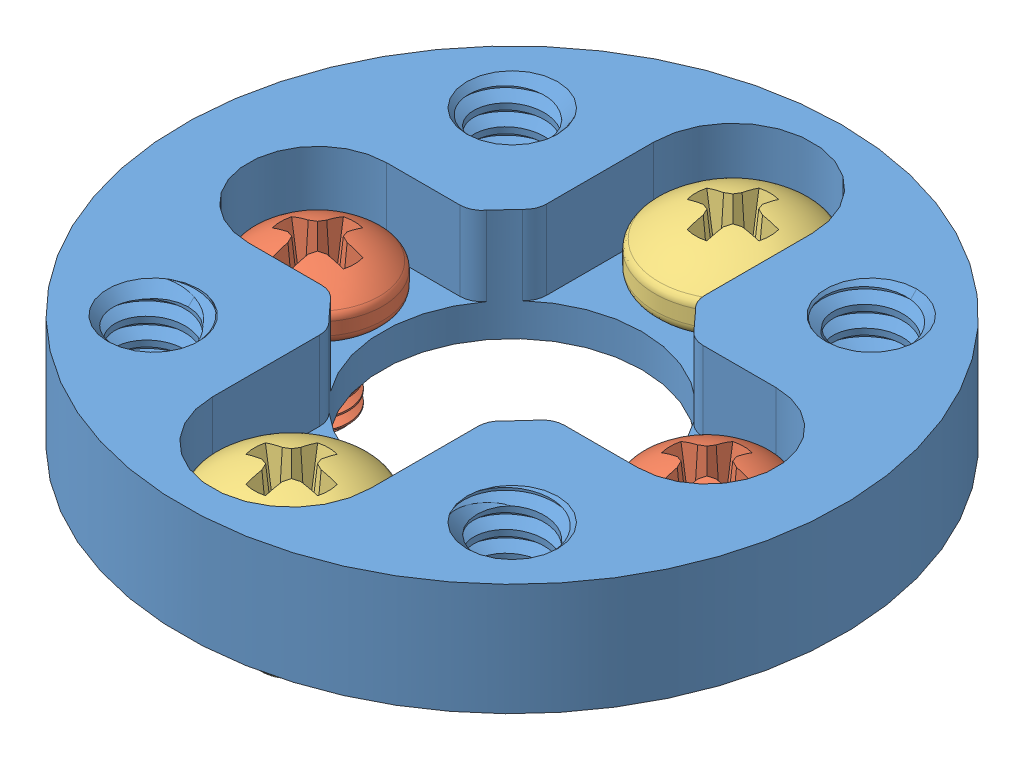
SolidWorks assembly Motor mount f, configuration Default. Lengths in mm.
Overall size (25.4 7.22 25.4).
5 component instances, 3 part files, 0 mates.
Components (placement in the parent):
- 555104-1: 555104 [Default] at (-70.4575 22.2385 20.6041) size (25.4 4.54 25.4)
- 555104 screw (M2.6)_92005A056-1: 555104 screw (M2.6)_92005A056 [Default] at (-77.9575 19.5085 20.6041) x (1 0 0) z (0 1 0) size (5 5 6.06)
- 555104 screw (M2.6)_92005A056-2: 555104 screw (M2.6)_92005A056 [Default] at (-62.9575 19.5085 20.6041) x (1 0 0) z (0 1 0) size (5 5 6.06)
- 555104 screw (M3)_92005A112-1: 555104 screw (M3)_92005A112 [Default] at (-70.4575 19.5085 12.1041) x (1 0 0) z (0 1 0) size (6 6 6.48)
- 555104 screw (M3)_92005A112-2: 555104 screw (M3)_92005A112 [Default] at (-70.4575 19.5085 29.1041) x (1 0 0) z (0 1 0) size (6 6 6.48)
